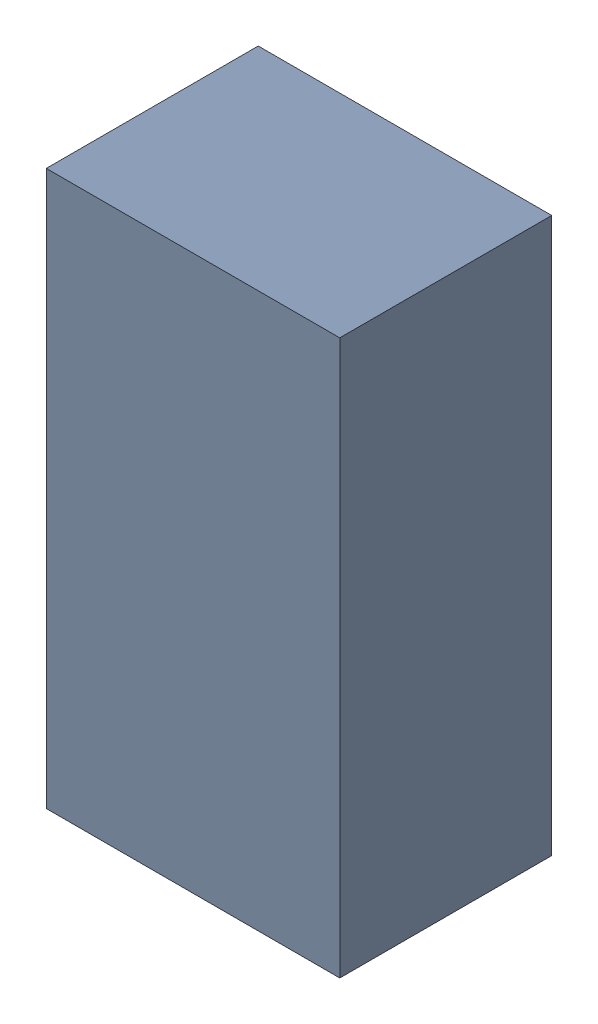
SolidWorks assembly C208, configuration Standard. Lengths in mm.
Overall size (1.8 3.4 1.3).
2 component instances, 1 part files, 0 mates.
Components (placement in the parent):
- 885541968-1: 885541968 [Standard] at (13.65 -23.05 0) size (1.8 3.4 1.3)
  - Extruded_30-1: Extruded_30 [Standard] at origin size (1.8 3.4 1.3)
